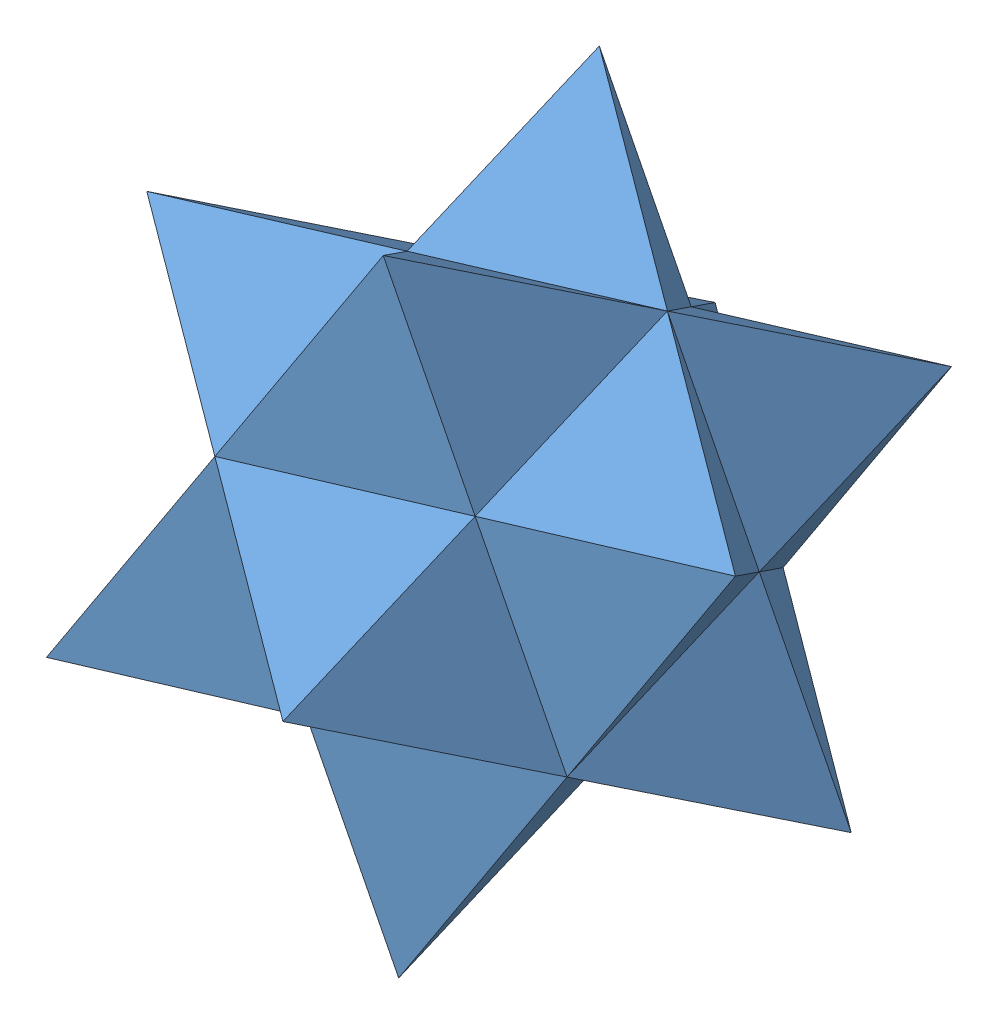
SolidWorks assembly Assem1, configuration Default. Lengths in mm.
Overall size (74.04 72.77 74).
6 component instances, 1 part files, 15 mates.
Components (placement in the parent):
- Pieza10.1-1: Pieza10.1 [Default] at (51.647 49.4917 26.9288) x (0.473021 0.84964 -0.233159) z (0.800974 -0.304462 0.515504) size (50.8 25.4 25.4)
- Pieza10.1-2: Pieza10.1 [Default] at (21.9804 68.1622 34.7788) x (0.473021 0.84964 -0.233159) z (-0.800974 0.304462 -0.515504) size (50.8 25.4 25.4)
- Pieza10.1-3: Pieza10.1 [Default] at (43.317 78.8059 7.9128) x (0.800974 -0.304462 0.515504) z (0.367005 -0.430598 -0.824556) size (50.8 25.4 25.4)
- Pieza10.1-4: Pieza10.1 [Default] at (21.9804 68.1622 34.7788) x (0.800974 -0.304462 0.515504) z (-0.367005 0.430598 0.824556) size (50.8 25.4 25.4)
- Pieza10.1-5: Pieza10.1 [Default] at (54.3398 82.0097 41.9503) x (0.367005 -0.430598 -0.824556) z (0.473021 0.84964 -0.233159) size (50.8 25.4 25.4)
- Pieza10.1-6: Pieza10.1 [Default] at (43.317 78.8059 7.9128) x (-0.367005 0.430598 0.824556) z (0.473021 0.84964 -0.233159) size (50.8 25.4 25.4)
Mates (geometry in assembly coordinates):
- Coincident2: coincident anti-aligned: line of Pieza10.1-2 through (54.3398 82.0097 41.9503) axis (-0.800974 0.304462 -0.515504); line of Pieza10.1-3 through (33.9951 89.743 28.8565) axis (0.800974 -0.304462 0.515504)
- Coincident3: coincident: point of Pieza10.1-2; point of Pieza10.1-3
- Coincident4: coincident anti-aligned: plane of Pieza10.1-2 through (23.3268 84.4212 42.2895) normal (-0.074964 -0.905265 -0.418181); plane of Pieza10.1-3 through (34.4911 98.9315 8.8767) normal (0.074964 0.905265 0.418181)
- Coincident5: coincident aligned: line of Pieza10.1-1 through (43.317 78.8059 7.9128) axis (0.800974 -0.304462 0.515504); line of Pieza10.1-3 through (43.317 78.8059 7.9128) axis (0.800974 -0.304462 0.515504)
- Coincident6: coincident: point of Pieza10.1-1; point of Pieza10.1-3
- Coincident7: coincident anti-aligned: plane of Pieza10.1-1 through (62.3154 54.8135 13.4959) normal (-0.593988 -0.296308 0.747917); plane of Pieza10.1-3 through (43.317 78.8059 7.9128) normal (0.593988 0.296308 -0.747917)
- Coincident8: coincident aligned: line of Pieza10.1-2 through (21.9804 68.1622 34.7788) axis (0.473021 0.84964 -0.233159); line of Pieza10.1-6 through (21.9804 68.1622 34.7788) axis (0.473021 0.84964 -0.233159)
- Coincident9: coincident: point of Pieza10.1-2; point of Pieza10.1-6
- Coincident10: coincident anti-aligned: plane of Pieza10.1-2 through (21.9804 68.1622 34.7788) normal (-0.306862 -0.089192 -0.947566); plane of Pieza10.1-6 through (48.8284 80.4078 24.9316) normal (0.306862 0.089192 0.947566)
- Coincident11: coincident aligned: line of Pieza10.1-1 through (51.647 49.4917 26.9288) axis (0.473021 0.84964 -0.233159); line of Pieza10.1-5 through (51.647 49.4917 26.9288) axis (0.473021 0.84964 -0.233159)
- Coincident12: coincident: point of Pieza10.1-1; point of Pieza10.1-5
- Coincident13: coincident anti-aligned: plane of Pieza10.1-1 through (51.647 49.4917 26.9288) normal (0.825886 -0.519766 -0.218533); plane of Pieza10.1-5 through (69.1732 72.6745 38.0254) normal (-0.825886 0.519766 0.218533)
- Coincident14: coincident anti-aligned: line of Pieza10.1-4 through (51.647 49.4917 26.9288) axis (-0.367005 0.430598 0.824556); line of Pieza10.1-5 through (42.3251 60.4289 47.8726) axis (0.367005 -0.430598 -0.824556)
- Coincident15: coincident anti-aligned: line of Pieza10.1-4 through (21.9804 68.1622 34.7788) axis (0.367005 -0.430598 -0.824556); line of Pieza10.1-6 through (31.3023 57.225 13.835) axis (-0.367005 0.430598 0.824556)
- Coincident16: coincident: point of Pieza10.1-2; point of Pieza10.1-4
